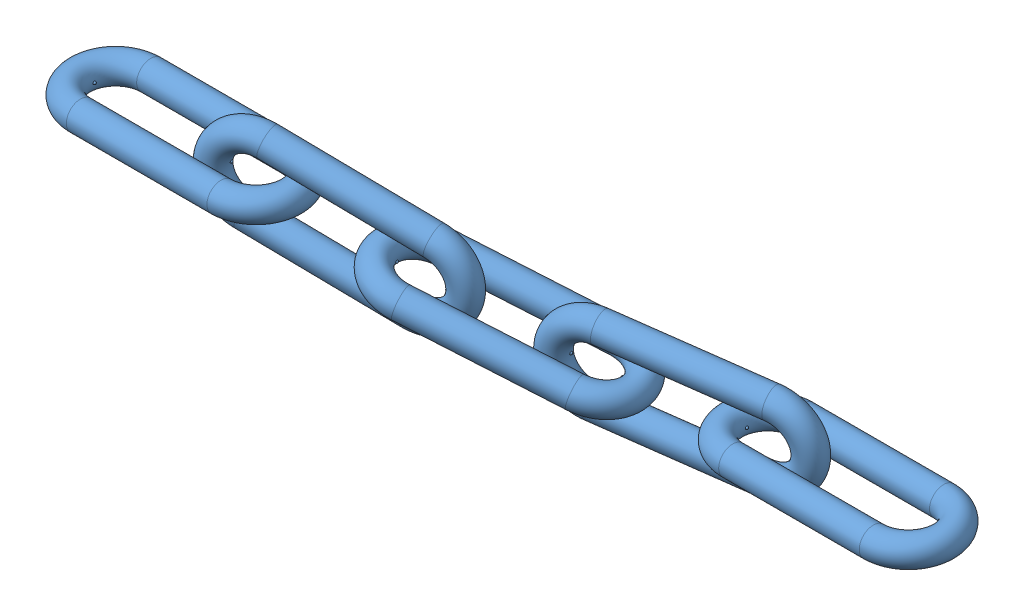
SolidWorks assembly 5chain, configuration Default. Lengths in mm.
Overall size (54.93 14.76 15.46).
5 component instances, 1 part files, 4 mates.
Components (placement in the parent):
- ChanLink-1: ChanLink [Default] at (-14.1366 4.836 4.1742) size (17 2 7)
- ChanLink-2: ChanLink [Default] at (-4.1366 4.836 4.1742) x (0.927165 -0.273194 -0.25638) z (-0.267581 -0.961834 0.057238) size (17 2 7)
- ChanLink-3: ChanLink [Default] at (5.135 2.1041 1.6104) x (0.90713 -0.261441 -0.329793) z (0.329989 -0.04449 0.942936) size (17 2 7)
- ChanLink-4: ChanLink [Default] at (14.2063 -0.5103 -1.6876) x (0.958738 -0.116009 -0.259543) z (-0.122411 -0.992442 -0.008581) size (17 2 7)
- ChanLink-5: ChanLink [Default] at (23.7937 -1.6704 -4.283) size (17 2 7)
Mates (geometry in assembly coordinates):
- Concentric2: concentric: sphere of ChanLink-1; sphere of ChanLink-2
- Concentric3: concentric: sphere of ChanLink-2; sphere of ChanLink-3
- Concentric4: concentric: sphere of ChanLink-3; sphere of ChanLink-4
- Concentric5: concentric: sphere of ChanLink-4; sphere of ChanLink-5
